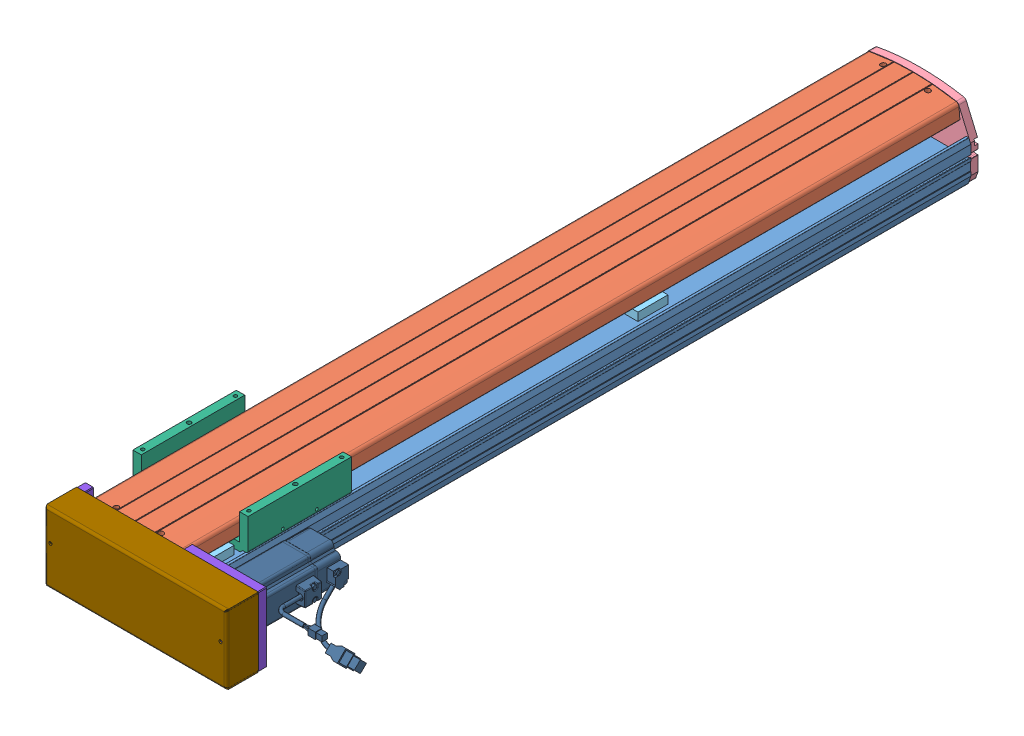
SolidWorks assembly S17M-BL-400W, configuration 默认. Lengths in mm.
Overall size (345.86 123.79 1201.01).
13 component instances, 10 part files, 43 mates.
Components (placement in the parent):
- T17-R-011底座^S17M-BL-400W-1: T17-R-011底座^S17M-BL-400W [默认] at origin size (170 60 1131) (virtual)
- T17S-L-007上盖^S17M-BL-400W-2: T17S-L-007上盖^S17M-BL-400W [Default] at (0 82 571.5) size (137.82 27.5 1143) (virtual)
- 672 传感器^S17M-BL-400W-1: 672 传感器^S17M-BL-400W [默认] at (-91.7485 42.15 968.8) x (-1 0 0) z (0 0 1) size (13.5 27.4 26.1) (virtual)
- 672 传感器^S17M-BL-400W-2: 672 传感器^S17M-BL-400W [默认] at (-91.7485 42.15 994.9) x (-1 0 0) z (0 0 1) size (13.5 27.4 26.1) (virtual)
- 672 传感器^S17M-BL-400W-3: 672 传感器^S17M-BL-400W [默认] at (-91.7485 42.15 165.35) x (-1 0 0) z (0 0 1) size (13.5 27.4 26.1) (virtual)
- CFT17S-L-001侧面板^S17M-BL-400W-1: CFT17S-L-001侧面板^S17M-BL-400W [默认] at (0 1 -11) size (169 101.5 11) (virtual)
- 滑座S17M^S17M-BL-400W-1: 滑座S17M^S17M-BL-400W [默认] at (0 75.7 432) x (-1 0 0) z (0 1 0) size (144.4 44 43.7) (virtual)
- 滑台S17M^S17M-BL-400W-1: 滑台S17M^S17M-BL-400W [默认] at (0 75.7 909) x (-1 0 0) z (0 1 0) size (169.2 152 78.7) (virtual)
- 滑座S17M^S17M-BL-400W-3: 滑座S17M^S17M-BL-400W [默认] at (0 75.7 1069) x (-1 0 0) z (0 1 0) size (144.4 44 43.7) (virtual)
-  外置感应片ST14-17^S17M-BL-400W-1:  外置感应片ST14-17^S17M-BL-400W [默认] at (-85.2 62.2 985) x (0 0 1) z (-1 0 0) size (70 30 7.6) (virtual)
- 电机板S17M-BL-60^S17M-BL-400W-1: 电机板S17M-BL-60^S17M-BL-400W [默认] at (48.3502 52.2 1131) size (267 102 12) (virtual)
- 罩壳S17M-BLR^S17M-BL-400W-1: 罩壳S17M-BLR^S17M-BL-400W [Default] at (48.3502 52.2 1188) x (1 0 0) z (0 0 -1) size (267.28 102.01 47.01) (virtual)
- 400W电机ECMA-C20604RS^S17M-BL-400W-1: 400W电机ECMA-C20604RS^S17M-BL-400W [Default] at (129.9985 49.95 1083.65) x (0 1 0) z (1 0 0) size (94.25 160.75 147.38) (virtual)
Mates (geometry in assembly coordinates):
- 重合148: coincident: plane of T17-R-011底座^S17M-BL-400W-1 through (0 0 0) normal (0 0 -1); plane of T17S-L-007上盖^S17M-BL-400W-2 through (66.7465 75.75 0) normal (0 0 -1)
- 重合153: coincident: plane of T17-R-011底座^S17M-BL-400W-1 through (0 0 0) normal (1 0 0); plane of T17S-L-007上盖^S17M-BL-400W-2 through (0 82 571.5) normal (1 0 0)
- 重合157: coincident: plane of 672 传感器^S17M-BL-400W-1 through (-84.9985 53.25 975.1) normal (1 0 0); plane of 672 传感器^S17M-BL-400W-3 through (-84.9985 53.25 171.65) normal (1 0 0)
- 重合158: coincident: plane of 672 传感器^S17M-BL-400W-1 through (-84.9985 53.25 975.1) normal (1 0 0); plane of 672 传感器^S17M-BL-400W-2 through (-84.9985 53.25 1001.2) normal (1 0 0)
- 重合159: coincident: plane of 672 传感器^S17M-BL-400W-1 through (-84.9985 53.25 975.1) normal (0 1 0); plane of 672 传感器^S17M-BL-400W-3 through (-84.9985 53.25 171.65) normal (0 1 0)
- 重合160: coincident: plane of 672 传感器^S17M-BL-400W-1 through (-84.9985 53.25 975.1) normal (0 1 0); plane of 672 传感器^S17M-BL-400W-2 through (-84.9985 53.25 1001.2) normal (0 1 0)
- 距离20: distance = 31.55 mm: plane of T17-R-011底座^S17M-BL-400W-1 through (0 -0.5 1131) normal (0 -1 0); plane of 672 传感器^S17M-BL-400W-2 through (-84.9985 31.05 1001.2) normal (0 -1 0)
- 距离21: distance = 165.35 mm: plane of 672 传感器^S17M-BL-400W-3 through (-98.4985 31.05 165.35) normal (0 0 -1); plane of T17-R-011底座^S17M-BL-400W-1 through (0 0 0) normal (0 0 -1)
- 重合168: coincident: plane of T17-R-011底座^S17M-BL-400W-1 through (-84.9985 0 1131) normal (-1 0 0); plane of 672 传感器^S17M-BL-400W-2 through (-84.9985 53.25 1001.2) normal (1 0 0)
- 重合169: coincident: plane of 672 传感器^S17M-BL-400W-1 through (-87.9985 34.25 985) normal (0 0 1); plane of 672 传感器^S17M-BL-400W-2 through (-87.9985 34.25 985) normal (0 0 -1)
- 重合174: coincident: plane of T17-R-011底座^S17M-BL-400W-1 through (0 0 0) normal (0 0 -1); plane of CFT17S-L-001侧面板^S17M-BL-400W-1 through (0.0037 -247.5005 0) normal (0 0 1)
- 重合183: coincident: plane of T17-R-011底座^S17M-BL-400W-1 through (0 0 0) normal (1 0 0); plane of CFT17S-L-001侧面板^S17M-BL-400W-1 through (0 1 -11) normal (1 0 0)
- 距离23: distance = 82.5 mm: plane of T17S-L-007上盖^S17M-BL-400W-2 through (0 82 571.5) normal (0 1 0); plane of T17-R-011底座^S17M-BL-400W-1 through (0 -0.5 1131) normal (0 -1 0)
- 距离26: distance = 1 mm: plane of T17-R-011底座^S17M-BL-400W-1 through (0 0 0) normal (0 1 0); plane of CFT17S-L-001侧面板^S17M-BL-400W-1 through (0 1 -11) normal (0 1 0)
- 重合211: coordinate: point of T17-R-011底座^S17M-BL-400W-1; point of assembly
- 距离27: distance = 110 mm: plane of 滑台S17M^S17M-BL-400W-1 through (-113.7999 109.5 909) normal (0 1 0); plane of T17-R-011底座^S17M-BL-400W-1 through (0 -0.5 1131) normal (0 -1 0)
- 宽度1: width: plane of 滑台S17M^S17M-BL-400W-1 through (-84.6 65.3 1061) normal (-1 0 0); plane of 滑台S17M^S17M-BL-400W-1 through (84.6 111.2 1061) normal (1 0 0); plane of T17-R-011底座^S17M-BL-400W-1 through (84.4985 0 1131) normal (1 0 0); plane of T17-R-011底座^S17M-BL-400W-1 through (-84.4985 0 1131) normal (-1 0 0)
- 宽度2: width: plane of 滑台S17M^S17M-BL-400W-1 through (-84.6 65.3 1061) normal (-1 0 0); plane of 滑台S17M^S17M-BL-400W-1 through (84.6 111.2 1061) normal (1 0 0); plane of 滑座S17M^S17M-BL-400W-1 through (72.2 32 476) normal (1 0 0); plane of 滑座S17M^S17M-BL-400W-1 through (-72.2 32 476) normal (-1 0 0)
- 距离29: distance = 5 mm: plane of 滑座S17M^S17M-BL-400W-1 through (40 70.7 476) normal (0 1 0); plane of 滑台S17M^S17M-BL-400W-1 through (-40 75.7 1061) normal (0 1 0)
- 重合221: coincident: plane of 滑座S17M^S17M-BL-400W-1 through (-40 75.7 476) normal (0 1 0); plane of 滑座S17M^S17M-BL-400W-3 through (-40 75.7 1113) normal (0 1 0)
- 重合222: coincident: plane of 滑座S17M^S17M-BL-400W-1 through (-72.2 32 476) normal (-1 0 0); plane of 滑座S17M^S17M-BL-400W-3 through (-72.2 32 1113) normal (-1 0 0)
- 距离30: distance = 8 mm: plane of 滑座S17M^S17M-BL-400W-3 through (81.6 65.3 1069) normal (0 0 -1); plane of 滑台S17M^S17M-BL-400W-1 through (81.6 65.3 1061) normal (0 0 1)
- 距离31: distance: plane of 滑座S17M^S17M-BL-400W-3 through (81.6 65.3 1069) normal (0 0 -1); plane of 滑座S17M^S17M-BL-400W-1 through (81.6 65.3 476) normal (0 0 1)
- 重合223: coincident: plane of 滑台S17M^S17M-BL-400W-1 through (-84.6 65.3 1061) normal (-1 0 0); plane of  外置感应片ST14-17^S17M-BL-400W-1 through (-84.6 62.2 985) normal (1 0 0)
- 同心121: concentric: cylinder of 滑台S17M^S17M-BL-400W-1 through (-84.6 68.2 960) axis (-1 0 0) radius 2.1; cylinder of  外置感应片ST14-17^S17M-BL-400W-1 through (-85.2 68.2 960) axis (-1 0 0) radius 2.75
- 同心122: concentric: cylinder of 滑台S17M^S17M-BL-400W-1 through (-84.6 68.2 1010) axis (-1 0 0) radius 2.1; cylinder of  外置感应片ST14-17^S17M-BL-400W-1 through (-85.2 68.2 1010) axis (-1 0 0) radius 2.75
- LimitDistance1: limit distance = 7.5 mm: line of 672 传感器^S17M-BL-400W-2 through (-87.9985 35.25 985) axis (0 1 0); plane of  外置感应片ST14-17^S17M-BL-400W-1 through (-85.2 60.6 977.5) normal (0 0 -1)
- 重合224: coincident: plane of T17-R-011底座^S17M-BL-400W-1 through (0 0 1131) normal (0 0 1); plane of 电机板S17M-BL-60^S17M-BL-400W-1 through (48.3502 52.2 1131) normal (0 0 -1)
- 距离32: distance = 1.7 mm: plane of 电机板S17M-BL-60^S17M-BL-400W-1 through (-85.1498 1.2 1143) normal (0 -1 0); plane of T17-R-011底座^S17M-BL-400W-1 through (0 -0.5 1131) normal (0 -1 0)
- 重合226: coincident: plane of T17-R-011底座^S17M-BL-400W-1 through (-84.9985 0 1131) normal (-1 0 0); plane of 电机板S17M-BL-60^S17M-BL-400W-1
- 重合227: coincident: plane of 电机板S17M-BL-60^S17M-BL-400W-1 through (48.3502 52.2 1143) normal (0 0 1); plane of 罩壳S17M-BLR^S17M-BL-400W-1 through (178.3502 103.2 1143) normal (0 0 -1)
- 重合228: coincident: plane of 电机板S17M-BL-60^S17M-BL-400W-1 through (181.8502 1.2 1143) normal (1 0 0); plane of 罩壳S17M-BLR^S17M-BL-400W-1 through (181.8502 52.2 1188) normal (1 0 0)
- 重合229: coincident: plane of 电机板S17M-BL-60^S17M-BL-400W-1 through (-85.1498 1.2 1143) normal (0 -1 0); plane of 罩壳S17M-BLR^S17M-BL-400W-1 through (48.3502 1.2 1188) normal (0 -1 0)
- 距离34: distance = 214 mm: line of 672 传感器^S17M-BL-400W-2 through (-87.9985 35.25 985) axis (0 1 0); plane of 罩壳S17M-BLR^S17M-BL-400W-1 through (48.3502 52.2 1190) normal (0 0 1)
- 重合230: coincident: plane of 电机板S17M-BL-60^S17M-BL-400W-1 through (48.3502 52.2 1131) normal (0 0 -1); plane of 400W电机ECMA-C20604RS^S17M-BL-400W-1 through (161.0442 18.9043 1131) normal (0 0 1)
- 平行1: parallel: plane of 电机板S17M-BL-60^S17M-BL-400W-1 through (-85.1498 103.2 1143) normal (0 1 0); plane of 400W电机ECMA-C20604RS^S17M-BL-400W-1 through (147.6785 79.95 1036.616) normal (0 1 0)
- 相切1: tangent: plane of 电机板S17M-BL-60^S17M-BL-400W-1 through (124.3502 24.95 1131) normal (0 1 0); cylinder of 400W电机ECMA-C20604RS^S17M-BL-400W-1 through (129.9985 49.95 1131) axis (0 0 1) radius 25
- 距离36: distance = 22 mm: line of 400W电机ECMA-C20604RS^S17M-BL-400W-1 through (159.8502 74.95 1131) axis (0 -1 0); plane of 电机板S17M-BL-60^S17M-BL-400W-1 through (181.8502 1.2 1143) normal (1 0 0)
- 距离37: distance = 45 mm: cylinder of 400W电机ECMA-C20604RS^S17M-BL-400W-1 through (129.9985 49.95 1160) axis (0 0 -1) radius 7; plane of T17-R-011底座^S17M-BL-400W-1 through (84.9985 0 1131) normal (1 0 0)
- 距离38: distance = 50.45 mm: cylinder of 400W电机ECMA-C20604RS^S17M-BL-400W-1 through (129.9985 49.95 1160) axis (0 0 -1) radius 7; plane of T17-R-011底座^S17M-BL-400W-1 through (0 -0.5 1131) normal (0 -1 0)
- 平行2: parallel: plane of T17-R-011底座^S17M-BL-400W-1 through (-84.9985 0 1131) normal (-1 0 0); plane of 电机板S17M-BL-60^S17M-BL-400W-1 through (-85.1498 1.2 1143) normal (-1 0 0)
- 距离40: distance = 205 mm: cylinder of 滑台S17M^S17M-BL-400W-1 through (78 111.2 985) axis (0 1 0) radius 3; plane of 罩壳S17M-BLR^S17M-BL-400W-1 through (48.3502 52.2 1190) normal (0 0 1)
- 宽度3: width: plane of 672 传感器^S17M-BL-400W-2 through (-98.4985 31.05 994.9) normal (0 0 -1); plane of 672 传感器^S17M-BL-400W-1 through (-98.4985 31.05 975.1) normal (0 0 1); plane of  外置感应片ST14-17^S17M-BL-400W-1 through (-92.2 60.6 992.5) normal (0 0 1); plane of  外置感应片ST14-17^S17M-BL-400W-1 through (-92.2 45.2 977.5) normal (0 0 -1)
